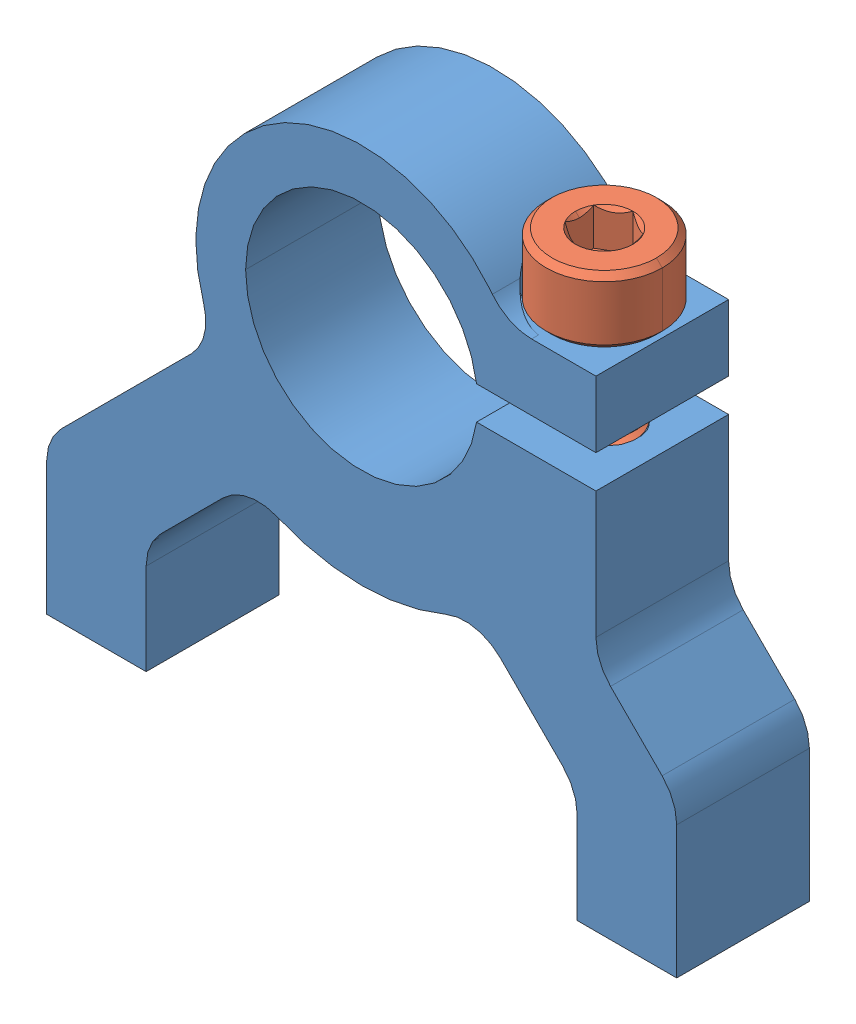
SolidWorks assembly 1-Side, 2-Post Clamping Mount (14mm Bore)1400-0032-0014, configuration Default. Lengths in mm.
Overall size (38 34 8).
2 component instances, 2 part files, 0 mates.
Components (placement in the parent):
- 1400-0032-0014.STEP-1: 1400-0032-0014.STEP [Default] at (-6.7355 7.0141 -0.371) size (38 34 8)
- 2800-0004-0012_90128A207.STEP-1: 2800-0004-0012_90128A207.STEP [Default] at (3.8927 0.0141 3.629) x (1 0 0) z (0 -1 0) size (7 7 16.01)
